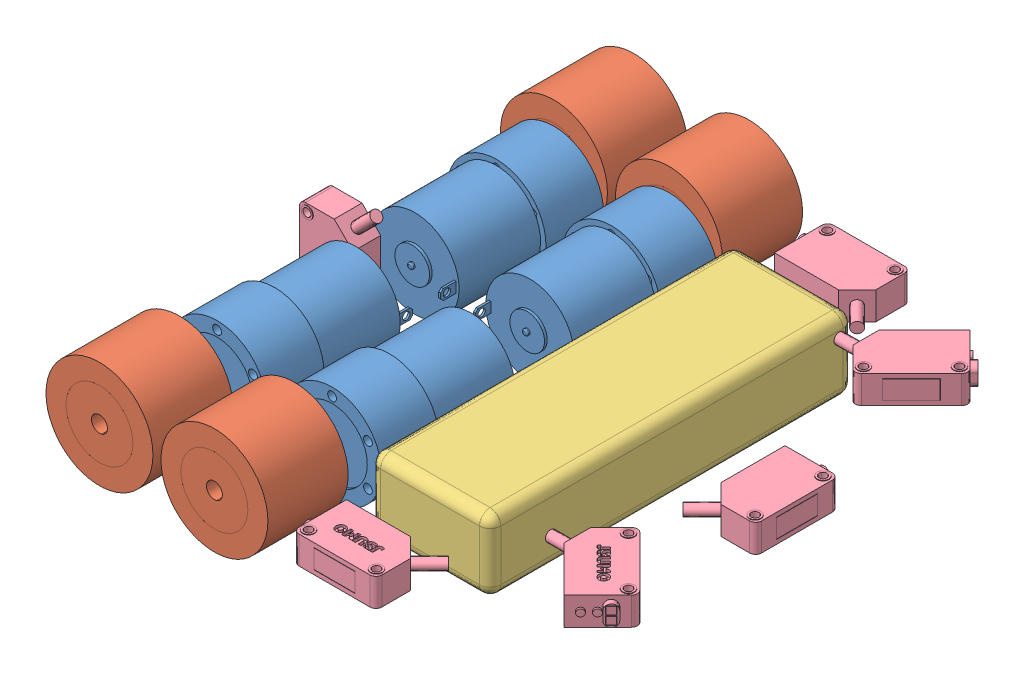
SolidWorks assembly ensamblaje2, configuration Predeterminado. Lengths in mm.
Overall size (200 40.49 200).
19 component instances, 4 part files, 10 mates.
Components (placement in the parent):
- Motor+Rueda-4: Motor+Rueda [Predeterminado] at (66.5149 60.1975 66.5157) x (-1 0 0) z (0 0 -1) size (45.5 40 94.75)
  - Titan-37mm-500rpm-2: Titan-37mm-500rpm [Predeterminado] at (-8.182 1.2078 75.625) x (0 1 0) z (0 0 1) size (37 37 78.75)
  - js4030-wheel-cad-1: js4030-wheel-cad [Predeterminado] at (-21.4262 1.7536 159.125) x (-1 0 0) z (0 0 -1) size (40 40 30)
- Motor+Rueda-6: Motor+Rueda [Predeterminado] at (66.5149 62.6131 -1.7343) x (-1 0 0) z (0 0 1) size (45.5 40 94.75)
  - Titan-37mm-500rpm-2: Titan-37mm-500rpm [Predeterminado] at (-8.182 1.2078 75.625) x (0 1 0) z (0 0 1) size (37 37 78.75)
  - js4030-wheel-cad-1: js4030-wheel-cad [Predeterminado] at (-21.4262 1.7536 159.125) x (-1 0 0) z (0 0 -1) size (40 40 30)
- Motor+Rueda-13: Motor+Rueda [Predeterminado] at (109.5149 60.1975 66.5157) x (-1 0 0) z (0 0 -1) size (45.5 40 94.75)
  - Titan-37mm-500rpm-2: Titan-37mm-500rpm [Predeterminado] at (-8.182 1.2078 75.625) x (0 1 0) z (0 0 1) size (37 37 78.75)
  - js4030-wheel-cad-1: js4030-wheel-cad [Predeterminado] at (-21.4262 1.7536 159.125) x (-1 0 0) z (0 0 -1) size (40 40 30)
- Motor+Rueda-14: Motor+Rueda [Predeterminado] at (109.5149 62.6131 -1.7343) x (-1 0 0) z (0 0 1) size (45.5 40 94.75)
  - Titan-37mm-500rpm-2: Titan-37mm-500rpm [Predeterminado] at (-8.182 1.2078 75.625) x (0 1 0) z (0 0 1) size (37 37 78.75)
  - js4030-wheel-cad-1: js4030-wheel-cad [Predeterminado] at (-21.4262 1.7536 159.125) x (-1 0 0) z (0 0 -1) size (40 40 30)
- Bateria-4: Bateria [Predeterminado] at (159.3196 44.4076 32.3907) x (0 0 -1) z (1 0 0) size (136 27 45)
- OMRON-E3Z-D62_D82-1: OMRON-E3Z-D62_D82 [Predeterminado] at (50.6947 74.1053 32.3907) x (1 0 0) z (0 0 -1) size (24.99 38.09 10.8)
- OMRON-E3Z-D62_D82-2: OMRON-E3Z-D62_D82 [Predeterminado] at (168.3091 57.9076 129.3907) x (0 0 -1) z (0 1 0) size (24.99 38.09 10.8)
- OMRON-E3Z-D62_D82-3: OMRON-E3Z-D62_D82 [Predeterminado] at (168.3091 57.9076 -64.6093) x (0 0 1) z (0 -1 0) size (24.99 38.09 10.8)
- OMRON-E3Z-D62_D82-4: OMRON-E3Z-D62_D82 [Predeterminado] at (221.6206 57.9076 41.0762) x (-1 0 0) z (0 -1 0) size (24.99 38.09 10.8)
- OMRON-E3Z-D62_D82-5: OMRON-E3Z-D62_D82 [Predeterminado] at (203.8412 57.9076 70.6456) x (-0.707107 0 0.707107) z (0 1 0) size (24.99 38.09 10.8)
- OMRON-E3Z-D62_D82-6: OMRON-E3Z-D62_D82 [Predeterminado] at (203.2997 67.4076 -17.7762) x (-0.707107 0 -0.707107) z (0 -1 0) size (24.99 38.09 10.8)
Mates (geometry in assembly coordinates):
- Concéntrica4: concentric anti-aligned: cylinder of Motor+Rueda-4/js4030-wheel-cad-1 through (67.6947 61.4053 -37.6093) axis (0 0 -1) radius 20; cylinder of Motor+Rueda-6/js4030-wheel-cad-1 through (67.6947 61.4053 102.3907) axis (0 0 1) radius 20
- Distancia4: distance = 200 mm anti-aligned: plane of Motor+Rueda-6/js4030-wheel-cad-1 through (67.6947 61.4053 132.3907) normal (0 0 1); plane of Motor+Rueda-4/js4030-wheel-cad-1 through (67.6947 61.4053 -67.6093) normal (0 0 -1)
- Ancho3: width aligned: plane of Bateria-4 through (181.8196 71.4076 100.3907) normal (0 0 1); plane of Bateria-4 through (181.8196 71.4076 -35.6093) normal (0 0 -1); plane of Motor+Rueda-13/js4030-wheel-cad-1 through (110.6947 61.4053 -67.6093) normal (0 0 1); plane of Motor+Rueda-14/js4030-wheel-cad-1 through (110.6947 61.4053 132.3907) normal (0 0 -1)
- Ancho4: width aligned: plane of OMRON-E3Z-D62_D82-1 through (47.6947 76.9053 37.5907) normal (0 1 0); plane of OMRON-E3Z-D62_D82-1 through (67.6947 45.9053 37.5907) normal (0 -1 0); plane of Motor+Rueda-4/Titan-37mm-500rpm-2 through (60.072 63.3512 21.3907) normal (0 1 0); plane of Motor+Rueda-4/Titan-37mm-500rpm-2 through (59.322 59.4594 21.3907) normal (0 -1 0)
- Ancho5: width aligned: plane of OMRON-E3Z-D62_D82-1 through (50.6947 74.1053 37.5907) normal (0 0 1); plane of OMRON-E3Z-D62_D82-1 through (50.6947 74.1053 27.1907) normal (0 0 -1); plane of Motor+Rueda-4/js4030-wheel-cad-1 through (67.6947 61.4053 -67.6093) normal (0 0 1); plane of Motor+Rueda-6/js4030-wheel-cad-1 through (67.6947 61.4053 132.3907) normal (0 0 -1)
- Coincidente1: coincident: plane of OMRON-E3Z-D62_D82-1 through (47.6947 45.9053 37.5907) normal (-1 0 0); line of assembly
- Coincidente3: coincident anti-aligned: plane of Motor+Rueda-13/js4030-wheel-cad-1 through (110.6947 61.4053 -67.6093) normal (0 0 1); plane of OMRON-E3Z-D62_D82-3 through (140.1091 63.1076 -67.6093) normal (0 0 -1)
- Coincidente4: coincident anti-aligned: plane of Motor+Rueda-14/js4030-wheel-cad-1 through (110.6947 61.4053 132.3907) normal (0 0 -1); plane of OMRON-E3Z-D62_D82-2 through (140.1091 52.7076 132.3907) normal (0 0 1)
- Coincidente5: coincident aligned: plane of OMRON-E3Z-D62_D82-2 through (168.3091 63.1076 129.3907) normal (0 1 0); plane of OMRON-E3Z-D62_D82-3 through (168.3091 63.1076 -64.6093) normal (0 1 0)
- Coincidente6: coincident aligned: plane of OMRON-E3Z-D62_D82-2 through (140.1091 52.7076 112.3907) normal (-1 0 0); plane of OMRON-E3Z-D62_D82-3 through (140.1091 63.1076 -47.6093) normal (-1 0 0)
